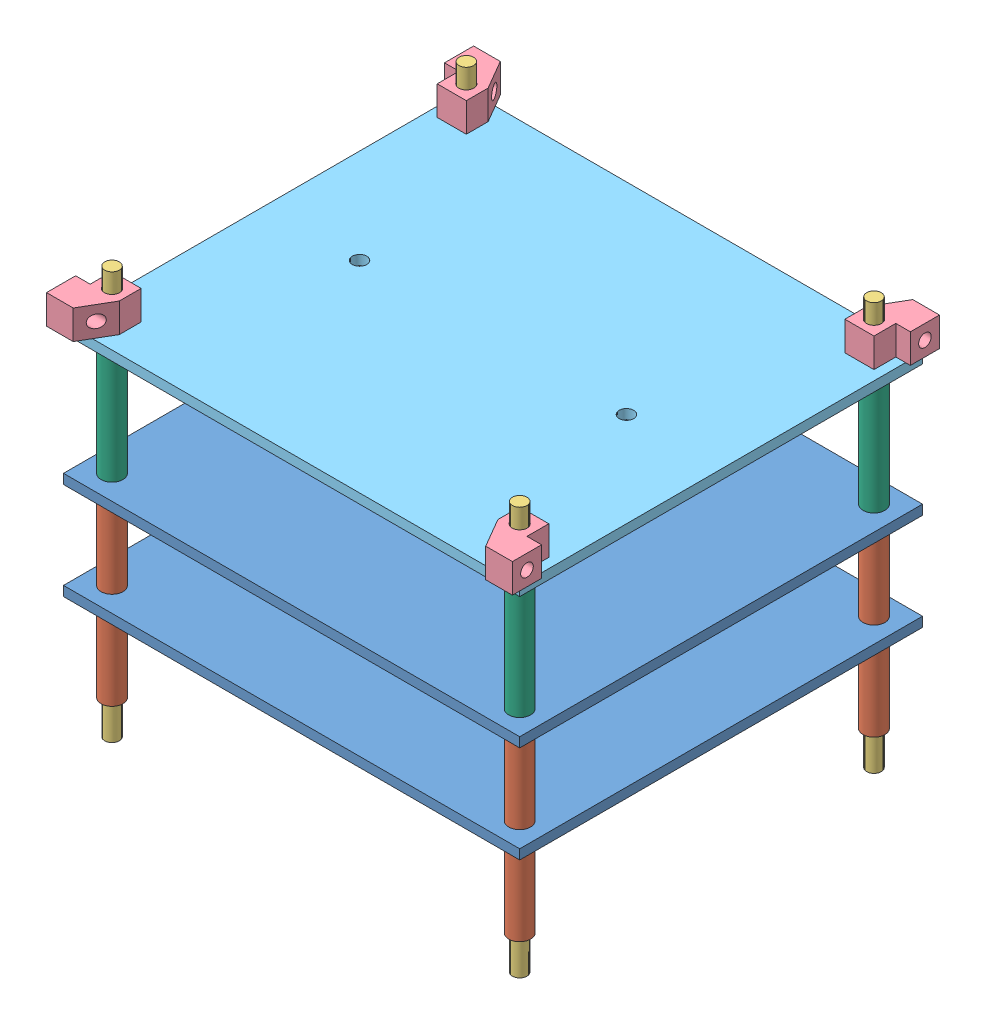
SolidWorks assembly PCB_Stack, configuration Default. Lengths in mm.
Overall size (96 84 88).
23 component instances, 6 part files, 49 mates.
Components (placement in the parent):
- PCB-1: PCB [Default] at (22.3374 37.9857 80.4453) size (94 2 83)
- 94669A105_Aluminum Unthreaded Spacer-1: 94669A105_Aluminum Unthreaded Spacer [94669A105] at (-19.6626 28.9857 116.9453) x (1 0 0) z (0 -1 0) size (4.5 4.5 18)
- 94669A105_Aluminum Unthreaded Spacer-2: 94669A105_Aluminum Unthreaded Spacer [94669A105] at (64.3374 28.9857 43.9453) x (-0.972016 0 0.234914) z (0 -1 0) size (4.5 4.5 18)
- 94669A105_Aluminum Unthreaded Spacer-3: 94669A105_Aluminum Unthreaded Spacer [94669A105] at (-19.6626 48.9857 116.9453) x (1 0 0) z (0 -1 0) size (4.5 4.5 18)
- 94669A105_Aluminum Unthreaded Spacer-4: 94669A105_Aluminum Unthreaded Spacer [94669A105] at (64.3374 48.9857 43.9453) x (0.999459 0 0.032887) z (0 -1 0) size (4.5 4.5 18)
- PCB_Rod-1: PCB_Rod [Default] at (-19.6626 12.9857 116.9453) x (0.637471 0 0.770474) z (-0.770474 0 0.637471) size (3 84 3)
- PCB-2: PCB [Default] at (22.3374 57.9857 80.4453) size (94 2 83)
- PCB_Rod-2: PCB_Rod [Default] at (64.3374 12.9857 43.9453) size (3 84 3)
- Mounting_Standoff-1: Mounting_Standoff [Default] at (22.3374 92.9857 80.4453) x (1 0 0) z (0 -1 0) size (9 10.5 6)
- Mounting_Standoff-2: Mounting_Standoff [Default] at (22.3374 92.9857 80.4453) x (-1 0 0) z (0 -1 0) size (9 10.5 6)
- PCB_Rod-3: PCB_Rod [Default] at (64.3374 12.9857 116.9453) x (0.307196 0 -0.951646) z (0.951646 0 0.307196) size (3 84 3)
- Mounting_Standoff-3: Mounting_Standoff [Default] at (22.3374 86.9857 80.4453) x (1 0 0) z (0 1 0) size (9 10.5 6)
- PCB_Rod-4: PCB_Rod [Default] at (-19.6626 12.9857 43.9453) size (3 84 3)
- Mounting_Standoff-4: Mounting_Standoff [Default] at (22.3374 86.9857 80.4453) x (-1 0 0) z (0 1 0) size (9 10.5 6)
- PCB_Battery-1: PCB_Battery [Default] at (22.3374 84.9857 80.4453) size (94 2 83)
- Aluminum Unthreaded Spacer_Battery-1: Aluminum Unthreaded Spacer_Battery [94669A105] at (64.3374 72.4857 116.9453) x (1 0 0) z (0 -1 0) size (4.5 4.5 25)
- Aluminum Unthreaded Spacer_Battery-2: Aluminum Unthreaded Spacer_Battery [94669A105] at (-19.6626 72.4857 116.9453) x (1 0 0) z (0 -1 0) size (4.5 4.5 25)
- Aluminum Unthreaded Spacer_Battery-3: Aluminum Unthreaded Spacer_Battery [94669A105] at (64.3374 72.4857 43.9453) x (1 0 0) z (0 -1 0) size (4.5 4.5 25)
- Aluminum Unthreaded Spacer_Battery-4: Aluminum Unthreaded Spacer_Battery [94669A105] at (-19.6626 72.4857 43.9453) x (1 0 0) z (0 -1 0) size (4.5 4.5 25)
- 94669A105_Aluminum Unthreaded Spacer-5: 94669A105_Aluminum Unthreaded Spacer [94669A105] at (64.3374 28.9857 116.9453) x (1 0 0) z (0 1 0) size (4.5 4.5 18)
- 94669A105_Aluminum Unthreaded Spacer-6: 94669A105_Aluminum Unthreaded Spacer [94669A105] at (-19.6626 28.9857 43.9453) x (1 0 0) z (0 1 0) size (4.5 4.5 18)
- 94669A105_Aluminum Unthreaded Spacer-7: 94669A105_Aluminum Unthreaded Spacer [94669A105] at (-19.6626 48.9857 43.9453) x (-0.837169 0 -0.546944) z (0 1 0) size (4.5 4.5 18)
- 94669A105_Aluminum Unthreaded Spacer-8: 94669A105_Aluminum Unthreaded Spacer [94669A105] at (64.3374 48.9857 116.9453) x (1 0 0) z (0 -1 0) size (4.5 4.5 18)
Mates (geometry in assembly coordinates):
- Coincident2: coincident: circle of PCB-1; plane of 94669A105_Aluminum Unthreaded Spacer-1 through (-19.6626 37.9857 116.9453) normal (0 1 0)
- Concentric4: concentric: circle of PCB-1; circle of 94669A105_Aluminum Unthreaded Spacer-2
- Coincident4: coincident: plane of PCB-1 through (22.3374 37.9857 80.4453) normal (0 -1 0); plane of 94669A105_Aluminum Unthreaded Spacer-2 through (64.3374 37.9857 43.9453) normal (0 1 0)
- Coincident5: coincident: circle of PCB-1; plane of 94669A105_Aluminum Unthreaded Spacer-3 through (-19.6626 39.9857 116.9453) normal (0 -1 0)
- Concentric5: concentric: cylinder of PCB-1 through (-19.6626 39.9857 116.9453) axis (0 -1 0) radius 1.5; cylinder of 94669A105_Aluminum Unthreaded Spacer-3 through (-19.6626 39.9857 116.9453) axis (0 1 0) radius 1.6
- Concentric6: concentric: circle of PCB-1; circle of 94669A105_Aluminum Unthreaded Spacer-4
- Coincident7: coincident: plane of PCB-1 through (22.3374 39.9857 80.4453) normal (0 1 0); plane of 94669A105_Aluminum Unthreaded Spacer-4 through (64.3374 39.9857 43.9453) normal (0 -1 0)
- Concentric7: concentric: cylinder of 94669A105_Aluminum Unthreaded Spacer-3 through (-19.6626 39.9857 116.9453) axis (0 1 0) radius 1.6; cylinder of PCB_Rod-1 through (-19.6626 96.9857 116.9453) axis (0 -1 0) radius 1.5
- Concentric8: concentric: circle of 94669A105_Aluminum Unthreaded Spacer-3; circle of PCB-2
- Coincident8: coincident: plane of 94669A105_Aluminum Unthreaded Spacer-3 through (-19.6626 57.9857 116.9453) normal (0 1 0); plane of PCB-2 through (22.3374 57.9857 80.4453) normal (0 -1 0)
- Concentric9: concentric: cylinder of 94669A105_Aluminum Unthreaded Spacer-4 through (64.3374 39.9857 43.9453) axis (0 1 0) radius 1.6; cylinder of PCB-2 through (64.3374 59.9857 43.9453) axis (0 -1 0) radius 1.5
- Coincident9: coincident: circle of PCB-2; cylinder of PCB_Rod-2 through (64.3374 96.9857 43.9453) axis (0 -1 0) radius 1.5
- Distance1: distance = 7 mm: plane of PCB_Rod-1 through (-19.6626 12.9857 116.9453) normal (0 -1 0); plane of 94669A105_Aluminum Unthreaded Spacer-1 through (-19.6626 19.9857 116.9453) normal (0 -1 0)
- Coincident15: coincident: plane of PCB_Rod-1 through (-19.6626 12.9857 116.9453) normal (0 -1 0); plane of PCB_Rod-2 through (64.3374 12.9857 43.9453) normal (0 -1 0)
- Concentric13: concentric: cylinder of PCB_Rod-2 through (64.3374 96.9857 43.9453) axis (0 -1 0) radius 1.5; cylinder of Mounting_Standoff-1 through (64.3374 86.9857 43.9453) axis (0 1 0) radius 1.55
- Concentric14: concentric: cylinder of PCB_Rod-1 through (-19.6626 96.9857 116.9453) axis (0 -1 0) radius 1.5; cylinder of Mounting_Standoff-2 through (-19.6626 86.9857 116.9453) axis (0 1 0) radius 1.55
- Coincident22: coincident: circle of PCB-1; cylinder of PCB_Rod-3 through (64.3374 96.9857 116.9453) axis (0 -1 0) radius 1.5
- Coincident24: coincident: plane of PCB_Rod-1 through (-19.6626 12.9857 116.9453) normal (0 -1 0); plane of PCB_Rod-3 through (64.3374 12.9857 116.9453) normal (0 -1 0)
- Coincident26: coincident: plane of Mounting_Standoff-2 through (22.3374 92.9857 80.4453) normal (0 1 0); plane of Mounting_Standoff-3 through (22.3374 92.9857 89.273) normal (0 1 0)
- Coincident28: coincident: plane of PCB_Rod-2 through (64.3374 12.9857 43.9453) normal (0 -1 0); plane of PCB_Rod-4 through (-19.6626 12.9857 43.9453) normal (0 -1 0)
- Concentric15: concentric: cylinder of PCB_Rod-4 through (-19.6626 96.9857 43.9453) axis (0 -1 0) radius 1.5; cylinder of Mounting_Standoff-4 through (-19.6626 92.9857 43.9453) axis (0 -1 0) radius 1.55
- Coincident29: coincident: plane of Mounting_Standoff-1 through (22.3374 92.9857 80.4453) normal (0 1 0); plane of Mounting_Standoff-4 through (22.3374 92.9857 80.4453) normal (0 1 0)
- Coincident32: coincident: cylinder of PCB_Rod-2 through (64.3374 96.9857 43.9453) axis (0 -1 0) radius 1.5; circle of PCB_Battery-1
- Coincident33: coincident: cylinder of PCB_Rod-4 through (-19.6626 96.9857 43.9453) axis (0 -1 0) radius 1.5; circle of PCB_Battery-1
- Coincident34: coincident: circle of PCB-1; cylinder of PCB_Rod-4 through (-19.6626 96.9857 43.9453) axis (0 -1 0) radius 1.5
- Concentric16: concentric: cylinder of 94669A105_Aluminum Unthreaded Spacer-1 through (-19.6626 19.9857 116.9453) axis (0 1 0) radius 1.6; cylinder of PCB_Rod-1 through (-19.6626 96.9857 116.9453) axis (0 -1 0) radius 1.5
- Concentric18: concentric: cylinder of PCB_Rod-4 through (-19.6626 96.9857 43.9453) axis (0 -1 0) radius 1.5; cylinder of Aluminum Unthreaded Spacer_Battery-4 through (-19.6626 59.9857 43.9453) axis (0 1 0) radius 1.6
- Concentric19: concentric: cylinder of PCB_Rod-2 through (64.3374 96.9857 43.9453) axis (0 -1 0) radius 1.5; cylinder of Aluminum Unthreaded Spacer_Battery-3 through (64.3374 59.9857 43.9453) axis (0 1 0) radius 1.6
- Concentric20: concentric: cylinder of PCB_Rod-3 through (64.3374 96.9857 116.9453) axis (0 -1 0) radius 1.5; cylinder of Aluminum Unthreaded Spacer_Battery-1 through (64.3374 59.9857 116.9453) axis (0 1 0) radius 1.6
- Concentric21: concentric: cylinder of PCB_Rod-1 through (-19.6626 96.9857 116.9453) axis (0 -1 0) radius 1.5; cylinder of Aluminum Unthreaded Spacer_Battery-2 through (-19.6626 59.9857 116.9453) axis (0 1 0) radius 1.6
- Coincident35: coincident: plane of PCB-2 through (22.3374 59.9857 80.4453) normal (0 1 0); plane of Aluminum Unthreaded Spacer_Battery-4 through (-19.6626 59.9857 43.9453) normal (0 -1 0)
- Coincident36: coincident: plane of PCB-2 through (22.3374 59.9857 80.4453) normal (0 1 0); plane of Aluminum Unthreaded Spacer_Battery-2 through (-19.6626 59.9857 116.9453) normal (0 -1 0)
- Coincident37: coincident: plane of PCB-2 through (22.3374 59.9857 80.4453) normal (0 1 0); plane of Aluminum Unthreaded Spacer_Battery-3 through (64.3374 59.9857 43.9453) normal (0 -1 0)
- Coincident38: coincident: plane of PCB-2 through (22.3374 59.9857 80.4453) normal (0 1 0); plane of Aluminum Unthreaded Spacer_Battery-1 through (64.3374 59.9857 116.9453) normal (0 -1 0)
- Coincident39: coincident: plane of PCB_Battery-1 through (22.3374 84.9857 80.4453) normal (0 -1 0); plane of Aluminum Unthreaded Spacer_Battery-3 through (64.3374 84.9857 43.9453) normal (0 1 0)
- Coincident40: coincident: plane of Mounting_Standoff-1 through (22.3374 86.9857 80.4453) normal (0 -1 0); plane of PCB_Battery-1 through (22.3374 86.9857 80.4453) normal (0 1 0)
- Coincident41: coincident: plane of Mounting_Standoff-1 through (22.3374 92.9857 80.4453) normal (0 1 0); plane of Mounting_Standoff-3 through (22.3374 92.9857 89.273) normal (0 1 0)
- Parallel1: parallel: line of Mounting_Standoff-1 through (61.3374 92.9857 46.9453) axis (0 0 -1); line of PCB_Battery-1 through (69.3374 86.9857 121.9453) axis (0 0 -1)
- Coincident43: coincident: line of Mounting_Standoff-1 through (61.3374 92.9857 46.9453) axis (0 0 -1); line of Mounting_Standoff-3 through (61.3374 92.9857 122.773) axis (0 0 1)
- Coincident44: coincident: line of Mounting_Standoff-2 through (-16.6626 92.9857 113.9453) axis (0 0 1); line of Mounting_Standoff-4 through (-16.6626 92.9857 46.9453) axis (0 0 -1)
- Coincident45: coincident: plane of PCB-1 through (22.3374 39.9857 80.4453) normal (0 1 0); plane of 94669A105_Aluminum Unthreaded Spacer-8 through (64.3374 39.9857 116.9453) normal (0 -1 0)
- Concentric23: concentric: cylinder of PCB_Rod-3 through (64.3374 96.9857 116.9453) axis (0 -1 0) radius 1.5; cylinder of 94669A105_Aluminum Unthreaded Spacer-8 through (64.3374 39.9857 116.9453) axis (0 1 0) radius 2.25
- Coincident46: coincident: plane of PCB-1 through (22.3374 39.9857 80.4453) normal (0 1 0); plane of 94669A105_Aluminum Unthreaded Spacer-7 through (-19.6626 39.9857 43.9453) normal (0 -1 0)
- Concentric25: concentric: cylinder of PCB_Rod-4 through (-19.6626 96.9857 43.9453) axis (0 -1 0) radius 1.5; cylinder of 94669A105_Aluminum Unthreaded Spacer-7 through (-19.6626 57.9857 43.9453) axis (0 -1 0) radius 2.25
- Coincident47: coincident: plane of PCB-1 through (22.3374 37.9857 80.4453) normal (0 -1 0); plane of 94669A105_Aluminum Unthreaded Spacer-5 through (64.3374 37.9857 116.9453) normal (0 1 0)
- Concentric26: concentric: cylinder of PCB_Rod-3 through (64.3374 96.9857 116.9453) axis (0 -1 0) radius 1.5; cylinder of 94669A105_Aluminum Unthreaded Spacer-5 through (64.3374 37.9857 116.9453) axis (0 -1 0) radius 2.25
- Coincident48: coincident: plane of PCB-1 through (22.3374 37.9857 80.4453) normal (0 -1 0); plane of 94669A105_Aluminum Unthreaded Spacer-6 through (-19.6626 37.9857 43.9453) normal (0 1 0)
- Concentric27: concentric: cylinder of PCB_Rod-4 through (-19.6626 96.9857 43.9453) axis (0 -1 0) radius 1.5; cylinder of 94669A105_Aluminum Unthreaded Spacer-6 through (-19.6626 37.9857 43.9453) axis (0 -1 0) radius 2.25
- Concentric28: concentric: cylinder of PCB_Rod-3 through (64.3374 96.9857 116.9453) axis (0 -1 0) radius 1.5; cylinder of Mounting_Standoff-3 through (64.3374 92.9857 116.9453) axis (0 -1 0) radius 1.55
